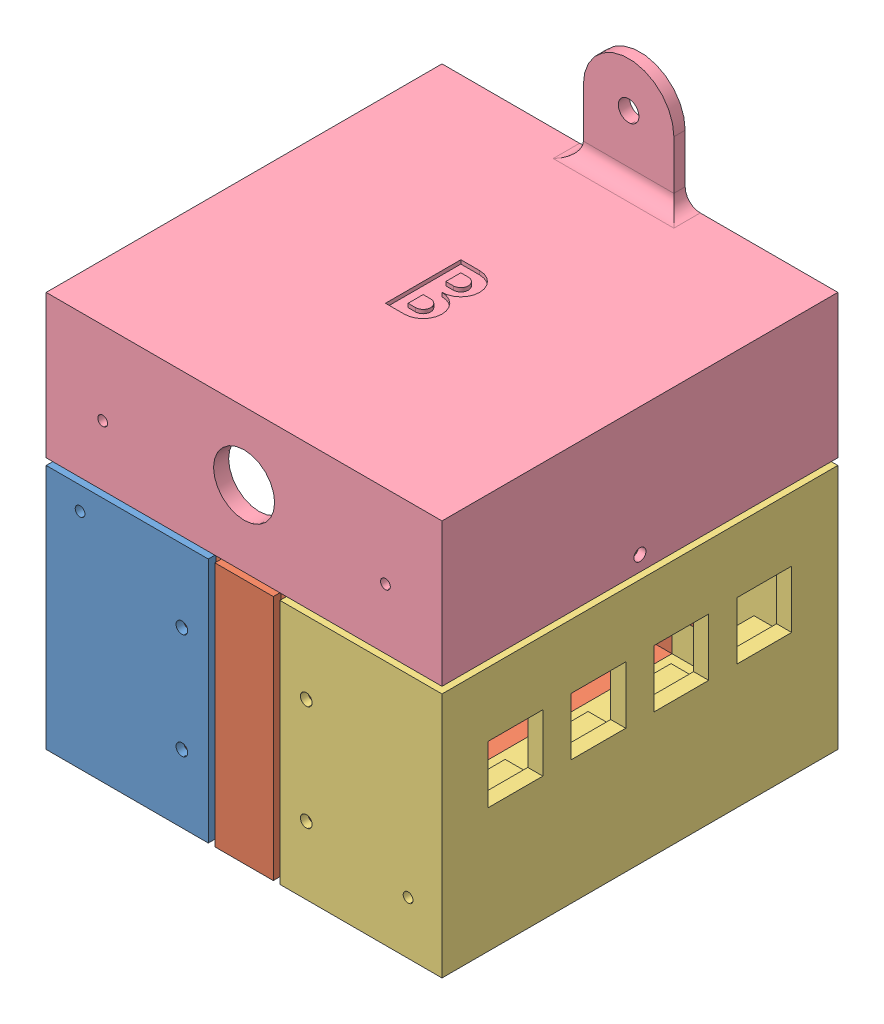
SolidWorks assembly Bbox, configuration Default. Lengths in mm.
Overall size (105 134 105).
4 component instances, 4 part files, 3 mates.
Components (placement in the parent):
- Bleft-1: Bleft [Default] at (-40.184 6.4053 16.8529) size (43 75 105)
- Bmiddle-1: Bmiddle [Default] at (18.8002 24.1666 105.1978) size (41 75 105)
- Bright-1: Bright [Default] at (78.9185 -7.4943 208.978) x (-1 0 0) z (0 0 -1) size (43 75 105)
- Btop-1: Btop [Default] at (18.8002 127.1666 105.1978) x (-1 0 0) z (0 0 1) size (105 67 105)
Mates (geometry in assembly coordinates):
- Coincident1: coincident: point of Bleft-1; point of Bmiddle-1
- Coincident2: coincident: point of Bmiddle-1; point of Bright-1
- Coincident3: coincident: point of Bright-1; point of Btop-1
